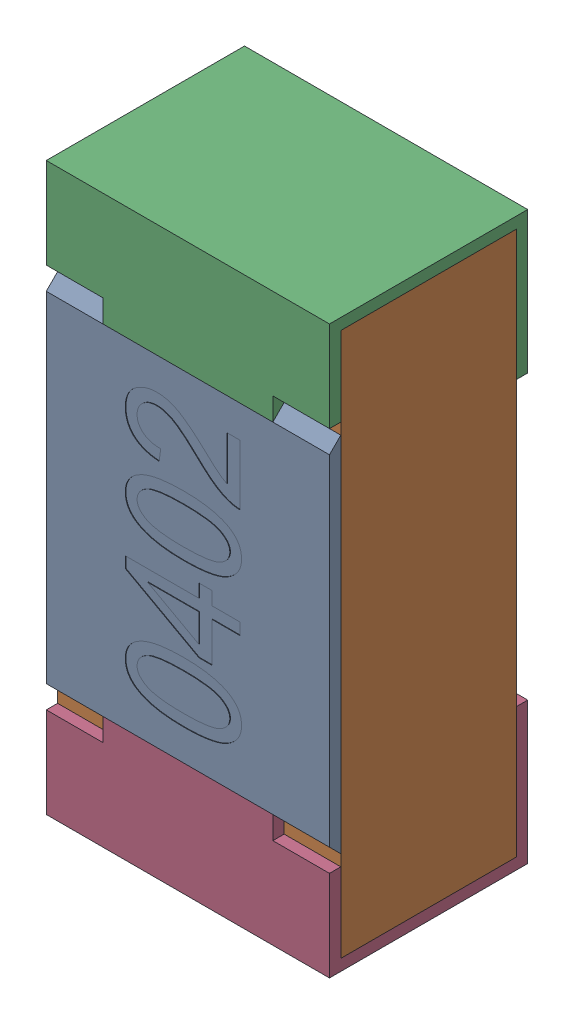
SolidWorks assembly R14, configuration Standard. Lengths in mm.
Overall size (0.5 1 0.35).
5 component instances, 4 part files, 0 mates.
Components (placement in the parent):
- R14-subassembly-1-1: R14-subassembly-1 [Standard] at (-3.1 18.1001 0) x (0 1 0) z (0 0 1) size (1 0.5 0.35)
  - User Library-R_0402-1: User Library-R_0402 [Standard] at origin size (0.64 0.5 0.02)
  - User Library-R_0402-1-1: User Library-R_0402-1 [Standard] at origin size (0.96 0.5 0.31)
  - User Library-R_0402-2-1: User Library-R_0402-2 [Standard] at origin size (0.25 0.5 0.35)
  - User Library-R_0402-3-1: User Library-R_0402-3 [Standard] at origin size (0.25 0.5 0.35)
